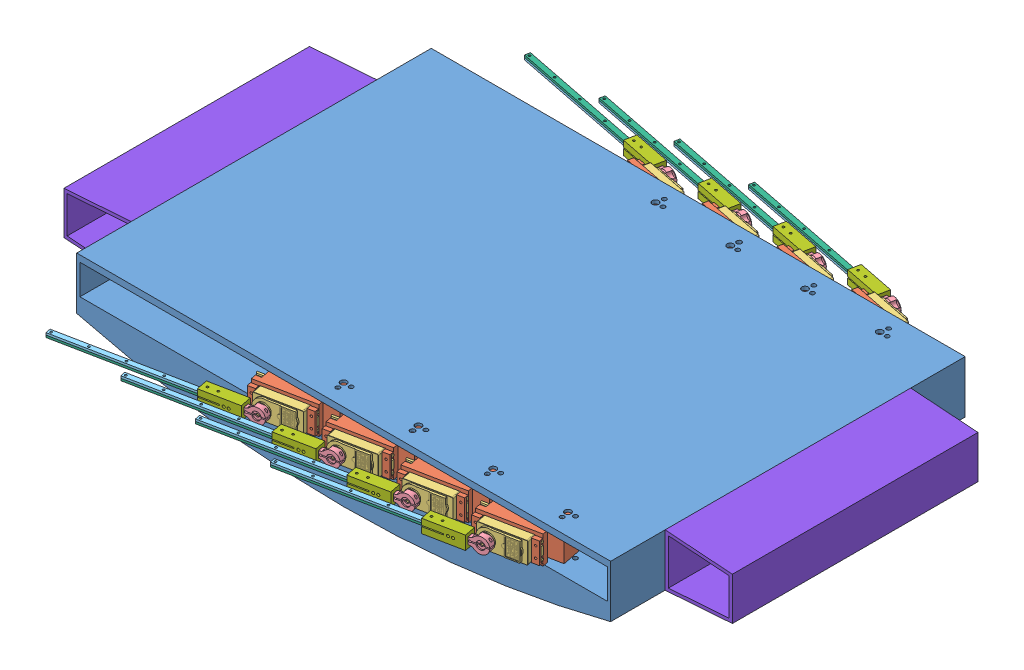
SolidWorks assembly Assem3, configuration Default. Lengths in mm.
Overall size (626 80.77 459.57).
59 component instances, 8 part files, 35 mates.
Components (placement in the parent):
- base-1: base [Default] at (-10.7828 359.6212 420.9172) size (500 80.77 332)
- servomech-1: servomech [Default] at (360.9588 423.8085 229.0625) x (-0.195261 0 0.980751) z (0.980751 0 0.195261) size (48.65 35 214.9)
  - Single Servo assembly v21-1: Single Servo assembly v21 [Default] at (49.7164 35.1874 34.3477) size (31.5 35 64.05)
  - Servo-1: Servo [Default] at (36.6438 35.1874 43.9482) x (0 0 -1) z (0 1 0) size (63.95 43.45 20)
  - Servo Horn v1-1: Servo Horn v1 [Default] at (-2.9962 35.1874 33.4982) x (0 0 -1) z (-1 0 0) size (34.33 14.5 6)
  - Component2-1: Component2 [Default] at (49.9664 34.9874 34.3477) size (4.8 2 140)
  - Component3-1: Component3 [Default] at (49.9664 35.1874 34.3477) size (4.8 2 140)
  - Component1-2: Component1 [Default] at (49.9664 35.1874 34.3477) size (10.8 12.5 35)
- servomech-2: servomech [Default] at (290.9588 423.8085 229.0625) x (-0.195261 0 0.980751) z (0.980751 0 0.195261) size (48.65 35 214.9)
  - Single Servo assembly v21-1: Single Servo assembly v21 [Default] at (49.7164 35.1874 34.3477) size (31.5 35 64.05)
  - Servo-1: Servo [Default] at (36.6438 35.1874 43.9482) x (0 0 -1) z (0 1 0) size (63.95 43.45 20)
  - Servo Horn v1-1: Servo Horn v1 [Default] at (-2.9962 35.1874 33.4982) x (0 0 -1) z (-1 0 0) size (34.33 14.5 6)
  - Component2-1: Component2 [Default] at (49.9664 34.9874 34.3477) size (4.8 2 140)
  - Component3-1: Component3 [Default] at (49.9664 35.1874 34.3477) size (4.8 2 140)
  - Component1-2: Component1 [Default] at (49.9664 35.1874 34.3477) size (10.8 12.5 35)
- servomech-3: servomech [Default] at (220.9588 423.8085 229.0625) x (-0.195261 0 0.980751) z (0.980751 0 0.195261) size (48.65 35 214.9)
  - Single Servo assembly v21-1: Single Servo assembly v21 [Default] at (49.7164 35.1874 34.3477) size (31.5 35 64.05)
  - Servo-1: Servo [Default] at (36.6438 35.1874 43.9482) x (0 0 -1) z (0 1 0) size (63.95 43.45 20)
  - Servo Horn v1-1: Servo Horn v1 [Default] at (-2.9962 35.1874 33.4982) x (0 0 -1) z (-1 0 0) size (34.33 14.5 6)
  - Component2-1: Component2 [Default] at (49.9664 34.9874 34.3477) size (4.8 2 140)
  - Component3-1: Component3 [Default] at (49.9664 35.1874 34.3477) size (4.8 2 140)
  - Component1-2: Component1 [Default] at (49.9664 35.1874 34.3477) size (10.8 12.5 35)
- servomech-4: servomech [Default] at (150.9588 423.8085 229.0625) x (-0.195261 0 0.980751) z (0.980751 0 0.195261) size (48.65 35 214.9)
  - Single Servo assembly v21-1: Single Servo assembly v21 [Default] at (49.7164 35.1874 34.3477) size (31.5 35 64.05)
  - Servo-1: Servo [Default] at (36.6438 35.1874 43.9482) x (0 0 -1) z (0 1 0) size (63.95 43.45 20)
  - Servo Horn v1-1: Servo Horn v1 [Default] at (-2.9962 35.1874 33.4982) x (0 0 -1) z (-1 0 0) size (34.33 14.5 6)
  - Component2-1: Component2 [Default] at (49.9664 34.9874 34.3477) size (4.8 2 140)
  - Component3-1: Component3 [Default] at (49.9664 35.1874 34.3477) size (4.8 2 140)
  - Component1-2: Component1 [Default] at (49.9664 35.1874 34.3477) size (10.8 12.5 35)
- servomech-5: servomech [Default] at (150.9588 353.4338 612.7719) x (-0.195261 0 -0.980751) z (0.980751 0 -0.195261) size (48.65 35 214.9)
  - Single Servo assembly v21-1: Single Servo assembly v21 [Default] at (49.7164 35.1874 34.3477) size (31.5 35 64.05)
  - Servo-1: Servo [Default] at (36.6438 35.1874 43.9482) x (0 0 -1) z (0 1 0) size (63.95 43.45 20)
  - Servo Horn v1-1: Servo Horn v1 [Default] at (-2.9962 35.1874 33.4982) x (0 0 -1) z (-1 0 0) size (34.33 14.5 6)
  - Component2-1: Component2 [Default] at (49.9664 34.9874 34.3477) size (4.8 2 140)
  - Component3-1: Component3 [Default] at (49.9664 35.1874 34.3477) size (4.8 2 140)
  - Component1-2: Component1 [Default] at (49.9664 35.1874 34.3477) size (10.8 12.5 35)
- servomech-6: servomech [Default] at (220.9588 353.4338 612.7719) x (-0.195261 0 -0.980751) z (0.980751 0 -0.195261) size (48.65 35 214.9)
  - Single Servo assembly v21-1: Single Servo assembly v21 [Default] at (49.7164 35.1874 34.3477) size (31.5 35 64.05)
  - Servo-1: Servo [Default] at (36.6438 35.1874 43.9482) x (0 0 -1) z (0 1 0) size (63.95 43.45 20)
  - Servo Horn v1-1: Servo Horn v1 [Default] at (-2.9962 35.1874 33.4982) x (0 0 -1) z (-1 0 0) size (34.33 14.5 6)
  - Component2-1: Component2 [Default] at (49.9664 34.9874 34.3477) size (4.8 2 140)
  - Component3-1: Component3 [Default] at (49.9664 35.1874 34.3477) size (4.8 2 140)
  - Component1-2: Component1 [Default] at (49.9664 35.1874 34.3477) size (10.8 12.5 35)
- servomech-7: servomech [Default] at (290.9588 353.4338 612.7719) x (-0.195261 0 -0.980751) z (0.980751 0 -0.195261) size (48.65 35 214.9)
  - Single Servo assembly v21-1: Single Servo assembly v21 [Default] at (49.7164 35.1874 34.3477) size (31.5 35 64.05)
  - Servo-1: Servo [Default] at (36.6438 35.1874 43.9482) x (0 0 -1) z (0 1 0) size (63.95 43.45 20)
  - Servo Horn v1-1: Servo Horn v1 [Default] at (-2.9962 35.1874 33.4982) x (0 0 -1) z (-1 0 0) size (34.33 14.5 6)
  - Component2-1: Component2 [Default] at (49.9664 34.9874 34.3477) size (4.8 2 140)
  - Component3-1: Component3 [Default] at (49.9664 35.1874 34.3477) size (4.8 2 140)
  - Component1-2: Component1 [Default] at (49.9664 35.1874 34.3477) size (10.8 12.5 35)
- servomech-8: servomech [Default] at (360.9588 353.4338 612.7719) x (-0.195261 0 -0.980751) z (0.980751 0 -0.195261) size (48.65 35 214.9)
  - Single Servo assembly v21-1: Single Servo assembly v21 [Default] at (49.7164 35.1874 34.3477) size (31.5 35 64.05)
  - Servo-1: Servo [Default] at (36.6438 35.1874 43.9482) x (0 0 -1) z (0 1 0) size (63.95 43.45 20)
  - Servo Horn v1-1: Servo Horn v1 [Default] at (-2.9962 35.1874 33.4982) x (0 0 -1) z (-1 0 0) size (34.33 14.5 6)
  - Component2-1: Component2 [Default] at (49.9664 34.9874 34.3477) size (4.8 2 140)
  - Component3-1: Component3 [Default] at (49.9664 35.1874 34.3477) size (4.8 2 140)
  - Component1-2: Component1 [Default] at (49.9664 35.1874 34.3477) size (10.8 12.5 35)
- base2-1: base2 [Default] at (489.2172 384.1212 305.9172) size (63 49 230)
- base2-2: base2 [Default] at (-10.7828 384.1212 305.9172) x (-1 0 0) z (0 0 1) size (63 49 230)
Mates (geometry in assembly coordinates):
- Concentric3: concentric aligned: circle of base-1; cylinder of servomech-5/Single Servo assembly v21-1 through (219.2172 401.6212 566.9172) axis (0 -1 0) radius 3
- Coincident4: coincident aligned: circle of base-1; cylinder of servomech-5/Single Servo assembly v21-1 through (220.584 401.6212 573.7825) axis (0 -1 0) radius 2
- Concentric4: concentric aligned: circle of base-1; cylinder of servomech-6/Single Servo assembly v21-1 through (289.2172 401.6212 566.9172) axis (0 -1 0) radius 3
- Concentric5: concentric aligned: circle of base-1; cylinder of servomech-6/Single Servo assembly v21-1 through (290.584 401.6212 573.7825) axis (0 -1 0) radius 2
- Concentric6: concentric aligned: circle of base-1; cylinder of servomech-7/Single Servo assembly v21-1 through (359.2172 401.6212 566.9172) axis (0 -1 0) radius 3
- Concentric7: concentric aligned: circle of base-1; cylinder of servomech-7/Single Servo assembly v21-1 through (360.584 401.6212 573.7825) axis (0 -1 0) radius 2
- Concentric9: concentric aligned: circle of base-1; circle of servomech-8/Single Servo assembly v21-1
- Concentric10: concentric aligned: circle of base-1; cylinder of servomech-8/Single Servo assembly v21-1 through (430.584 401.6212 573.7825) axis (0 -1 0) radius 2
- Parallel1: parallel anti-aligned: plane of base-1 through (-10.7828 374.6212 420.9172) normal (0 1 0); plane of servomech-1/Single Servo assembly v21-1 through (378.1763 375.6212 244.8726) normal (0 -1 0)
- Concentric11: concentric anti-aligned: circle of base-1; cylinder of servomech-1/Single Servo assembly v21-1 through (429.2172 375.6212 274.9172) axis (0 1 0) radius 3
- Concentric12: concentric anti-aligned: circle of base-1; cylinder of servomech-1/Single Servo assembly v21-1 through (430.584 375.6212 268.0519) axis (0 1 0) radius 2
- Parallel2: parallel anti-aligned: plane of base-1 through (-10.7828 374.6212 420.9172) normal (0 1 0); plane of servomech-2/Single Servo assembly v21-1 through (308.1763 375.6212 244.8726) normal (0 -1 0)
- Concentric13: concentric anti-aligned: circle of base-1; cylinder of servomech-2/Single Servo assembly v21-1 through (359.2172 375.6212 274.9172) axis (0 1 0) radius 3
- Concentric14: concentric anti-aligned: circle of base-1; cylinder of servomech-2/Single Servo assembly v21-1 through (360.584 375.6212 268.0519) axis (0 1 0) radius 2
- Concentric15: concentric anti-aligned: circle of base-1; cylinder of servomech-3/Single Servo assembly v21-1 through (289.2172 375.6212 274.9172) axis (0 1 0) radius 3
- Concentric16: concentric anti-aligned: circle of base-1; cylinder of servomech-3/Single Servo assembly v21-1 through (290.584 375.6212 268.0519) axis (0 1 0) radius 2
- Parallel3: parallel anti-aligned: plane of base-1 through (-10.7828 374.6212 420.9172) normal (0 1 0); plane of servomech-4/Single Servo assembly v21-1 through (168.1763 375.6212 244.8726) normal (0 -1 0)
- Concentric19: concentric anti-aligned: circle of base-1; cylinder of servomech-4/Single Servo assembly v21-1 through (219.2172 375.6212 274.9172) axis (0 1 0) radius 3
- Concentric20: concentric anti-aligned: circle of base-1; cylinder of servomech-4/Single Servo assembly v21-1 through (220.584 375.6212 268.0519) axis (0 1 0) radius 2
- Concentric21: concentric anti-aligned: circle of base-1; cylinder of servomech-4/Single Servo assembly v21-1 through (219.2172 375.6212 274.9172) axis (0 1 0) radius 3
- Concentric22: concentric anti-aligned: circle of base-1; cylinder of servomech-4/Single Servo assembly v21-1 through (220.584 375.6212 268.0519) axis (0 1 0) radius 2
- Width1: width aligned: plane of base-1 through (-10.7828 374.6212 420.9172) normal (0 1 0); plane of base-1 through (-10.7828 402.6212 420.9172) normal (0 -1 0); plane of servomech-1/Single Servo assembly v21-1 through (424.2471 401.6212 254.045) normal (0 1 0); plane of servomech-1/Single Servo assembly v21-1 through (378.1763 375.6212 244.8726) normal (0 -1 0)
- Width2: width: plane of servomech-2/Single Servo assembly v21-1 through (354.2471 401.6212 254.045) normal (0 1 0); plane of servomech-2/Single Servo assembly v21-1 through (308.1763 375.6212 244.8726) normal (0 -1 0); plane of base-1 through (-10.7828 374.6212 420.9172) normal (0 1 0); plane of base-1 through (-10.7828 402.6212 420.9172) normal (0 -1 0)
- Width3: width aligned: plane of base-1 through (-10.7828 374.6212 420.9172) normal (0 1 0); plane of base-1 through (-10.7828 402.6212 420.9172) normal (0 -1 0); plane of servomech-3/Single Servo assembly v21-1 through (284.2471 401.6212 254.045) normal (0 1 0); plane of servomech-3/Single Servo assembly v21-1 through (238.1763 375.6212 244.8726) normal (0 -1 0)
- Width4: width aligned: plane of base-1 through (-10.7828 374.6212 420.9172) normal (0 1 0); plane of base-1 through (-10.7828 402.6212 420.9172) normal (0 -1 0); plane of servomech-4/Single Servo assembly v21-1 through (214.2471 401.6212 254.045) normal (0 1 0); plane of servomech-4/Single Servo assembly v21-1 through (168.1763 375.6212 244.8726) normal (0 -1 0)
- Width5: width: plane of servomech-5/Single Servo assembly v21-1 through (168.1763 401.6212 596.9618) normal (0 1 0); plane of servomech-5/Single Servo assembly v21-1 through (214.2471 375.6212 587.7894) normal (0 -1 0); plane of base-1 through (-10.7828 374.6212 420.9172) normal (0 1 0); plane of base-1 through (-10.7828 402.6212 420.9172) normal (0 -1 0)
- Width6: width: plane of servomech-7/Single Servo assembly v21-1 through (308.1763 401.6212 596.9618) normal (0 1 0); plane of servomech-7/Single Servo assembly v21-1 through (354.2471 375.6212 587.7894) normal (0 -1 0); plane of base-1 through (-10.7828 374.6212 420.9172) normal (0 1 0); plane of base-1 through (-10.7828 402.6212 420.9172) normal (0 -1 0)
- Width7: width: plane of servomech-6/Single Servo assembly v21-1 through (238.1763 401.6212 596.9618) normal (0 1 0); plane of servomech-6/Single Servo assembly v21-1 through (284.2471 375.6212 587.7894) normal (0 -1 0); plane of base-1 through (-10.7828 374.6212 420.9172) normal (0 1 0); plane of base-1 through (-10.7828 402.6212 420.9172) normal (0 -1 0)
- Width8: width: plane of servomech-8/Single Servo assembly v21-1 through (424.2471 375.6212 587.7894) normal (0 -1 0); plane of servomech-8/Single Servo assembly v21-1 through (378.1763 401.6212 596.9618) normal (0 1 0); plane of base-1 through (-10.7828 402.6212 420.9172) normal (0 -1 0); plane of base-1 through (-10.7828 374.6212 420.9172) normal (0 1 0)
- Width9: width anti-aligned: plane of base-1 through (239.2172 1327.2215 254.9172) normal (0 0 -1); plane of base2-1 through (239.2172 1327.2215 586.9172) normal (0 0 1); plane of base-1 through (489.2172 384.1212 535.9172) normal (0 0 1); plane of base2-1 through (489.2172 384.1212 305.9172) normal (0 0 -1)
- Coincident28: coincident anti-aligned: plane of base-1 through (489.2172 359.6212 586.9172) normal (1 0 0); plane of base2-1 through (489.2172 359.6212 535.9172) normal (-1 0 0)
- Coincident30: coincident aligned: line of base-1 through (489.2172 359.6212 586.9172) axis (0 0 -1); line of base2-1 through (489.2172 359.6212 535.9172) axis (0 0 -1)
- Width10: width: plane of base-1 through (239.2172 1327.2215 254.9172) normal (0 0 -1); plane of base2-2 through (239.2172 1327.2215 586.9172) normal (0 0 1); plane of base-1 through (-10.7828 340.3957 535.9172) normal (0 0 1); plane of base2-2 through (-10.7828 340.3957 305.9172) normal (0 0 -1)
- Coincident32: coincident: plane of base-1 through (-10.7828 359.6212 586.9172) normal (-1 0 0); plane of base2-2 through (-10.7828 408.6212 535.9172) normal (1 0 0)
- Coincident33: coincident aligned: line of base-1 through (-10.7828 408.6212 586.9172) axis (0 0 -1); line of base2-2 through (-10.7828 408.6212 535.9172) axis (0 0 -1)
